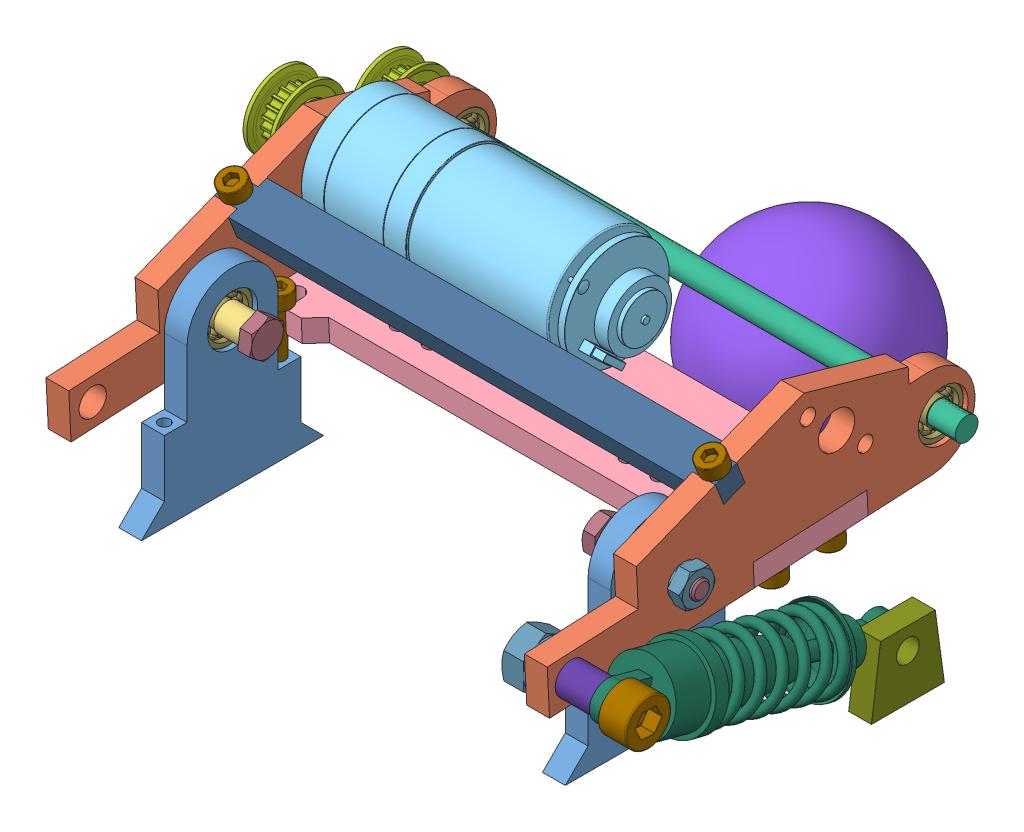
SolidWorks assembly tribla-better-assembly, configuration Default. Lengths in mm.
Overall size (140.2 70.72 132.36).
38 component instances, 17 part files, 67 mates.
Components (placement in the parent):
- tribla-jalg-4: tribla-jalg [Default] at (0.7792 -42.4947 66.2972) size (5 42 40)
- tribla-jalg-5: tribla-jalg [Default] at (93.7792 -42.4947 66.2972) size (5 42 40)
- tribla-side-3: tribla-side [Default] at (-0.2208 -6.2566 33.7735) x (0 -0.050794 0.998709) z (-1 0 0) size (94 31 5)
- tribla-little-ring-5: tribla-little-ring [Default] at (-5.2208 -10.4947 66.2972) x (0 -0.211085 -0.977468) z (0 -0.977468 0.211085) size (6 6 6)
- stabiliti-plane-2: stabiliti-plane [Default] at (104.7792 -19.82 40.9277) x (-1 0 0) z (0 0.050794 -0.998709) size (110 5 27)
- Pololu 25D gear motor with encoder part no 2275-2: Pololu 25D gear motor with encoder part no 2275 [Default] at (4.7792 1.2239 32.762) x (0 -0.679948 -0.73326) z (-1 0 0) size (25 25 75.81)
- tribla-little-ring-6: tribla-little-ring [Default] at (4.6292 -10.4947 66.2972) x (0 0.653622 -0.756821) z (0 -0.756821 -0.653622) size (6 6 6)
- tribla-side-4: tribla-side [Default] at (104.7792 -6.2566 33.7735) x (0 -0.050794 0.998709) z (-1 0 0) size (94 31 5)
- tribla-voll-2: tribla-voll [Default] at (47.3698 -10.4088 11.7103) x (-1 0 0) z (0 0.768447 -0.639913) size (120 5 5)
- tribla-rihmaratas'-3: tribla-rihmaratas' [Default] at (-10.8208 1.2239 32.762) x (0 0.354819 -0.934935) z (1 0 0) size (16.1 16.1 12.2)
- tribla-rihmaratas'-4: tribla-rihmaratas' [Default] at (-10.8208 -7.5994 9.3708) x (0 0.513074 -0.858344) z (1 0 0) size (16.1 16.1 12.2)
- tribla-little-ring-7: tribla-little-ring [Default] at (104.7792 -10.4947 66.2972) x (0 -0.429217 0.903201) z (0 -0.903201 -0.429217) size (6 6 6)
- tribla-little-ring-8: tribla-little-ring [Default] at (88.7792 -10.4947 66.2972) x (0 -0.057805 -0.998328) z (0 -0.998328 0.057805) size (6 6 6)
- ball-1: ball [Default] at (53.0779 -30.3345 -12.9168) size (43 43 43)
- socket head cap screw_iso-1: socket head cap screw_iso [ISO 4762 M3 x 10 --- 10C] at (96.2792 -21.8765 53.7972) x (0 -1 0) z (0.622703 0 0.782458) size (13 5.5 5.5)
- tribla-small-support-1: tribla-small-support [Default] at (104.7792 5.2258 53.9342) x (0 -0.368295 0.929709) z (-1 0 0) size (9 5 110)
- socket head cap screw_iso-4: socket head cap screw_iso [ISO 4762 M3 x 12 --- 12C] at (102.277 7.8744 58.1441) x (0 -0.929709 -0.368295) z (-0.694748 0.264898 -0.668696) size (15 5.5 5.5)
- socket head cap screw_iso-5: socket head cap screw_iso [ISO 4762 M3 x 12 --- 12C] at (-2.7185 7.8744 58.1441) x (0 -0.929709 -0.368295) z (-0.38626 0.339712 -0.857554) size (15 5.5 5.5)
- socket head cap screw_iso-6: socket head cap screw_iso [ISO 4762 M3 x 10 --- 10C] at (-2.7208 -22.3985 44.4143) x (0 0.998709 0.050794) z (-0.091557 -0.050581 0.994514) size (13 5.5 5.5)
- socket head cap screw_iso-7: socket head cap screw_iso [ISO 4762 M3 x 10 --- 10C] at (102.2792 -21.7636 31.9305) x (0 0.998709 0.050794) z (-0.091557 -0.050581 0.994514) size (13 5.5 5.5)
- socket head cap screw_iso-8: socket head cap screw_iso [ISO 4762 M3 x 10 --- 10C] at (-2.7208 -21.7636 31.9305) x (0 0.998709 0.050794) z (-0.091557 -0.050581 0.994514) size (13 5.5 5.5)
- socket head cap screw_iso-9: socket head cap screw_iso [ISO 4762 M3 x 10 --- 10C] at (102.2792 -22.3985 44.4143) x (0 0.998709 0.050794) z (-0.091557 -0.050581 0.994514) size (13 5.5 5.5)
- socket countersunk head screw_iso-3: socket countersunk head screw_iso [ISO 10642 - M3 x 12 --- 12C] at (-5.2208 -4.4735 26.4541) x (1 0 0) z (0 -0.048949 0.998801) size (12 5.54 5.54)
- socket countersunk head screw_iso-4: socket countersunk head screw_iso [ISO 10642 - M3 x 12 --- 12C] at (-5.2208 6.9212 39.07) x (1 0 0) z (0 0.256767 0.966473) size (12 5.54 5.54)
- socket head cap screw_iso-10: socket head cap screw_iso [ISO 4762 M3 x 20 --- 20N] at (3.2792 -11.5874 53.7972) x (0 -1 0) z (-0.920539 0 0.390651) size (23 5.5 5.5)
- angular contact ball bearing_68_iso-2: angular contact ball bearing_68_iso [ISO 15 ABB - 194 - Full,DE,AC,Full_68] at (-2.2208 -7.5994 9.3708) size (4 11 11)
- angular contact ball bearing_68_iso-3: angular contact ball bearing_68_iso [ISO 15 ABB - 194 - Full,DE,AC,Full_68] at (101.7792 -7.5994 9.3708) size (4 11 11)
- angular contact ball bearing_68_iso-4: angular contact ball bearing_68_iso [ISO 15 ABB - 194 - Full,DE,AC,Full_68] at (2.7792 -10.4947 66.2972) x (1 0 0) z (0 -0.345027 0.938593) size (4 11 11)
- angular contact ball bearing_68_iso-5: angular contact ball bearing_68_iso [ISO 15 ABB - 194 - Full,DE,AC,Full_68] at (96.7792 -10.4947 66.2972) size (4 11 11)
- hex bolt gradeb_iso-1: hex bolt gradeb_iso [ISO 4015 - M4 x 20 x 14-C] at (85.9792 -10.4947 66.2972) size (22.8 8.08 7)
- hex bolt gradeb_iso-2: hex bolt gradeb_iso [ISO 4015 - M4 x 20 x 14-C] at (13.4292 -10.4947 66.2972) x (-1 0 0) z (0 -0.924225 -0.381849) size (22.8 8.08 7)
- hex nut style 1 gradeab_iso-2: hex nut style 1 gradeab_iso [Hexagon Nut ISO - 4032 - M4 - W - N] at (-8.4208 -10.4947 66.2972) x (0 0.707107 0.707107) z (-1 0 0) size (7 8.08 3.2)
- hex nut style 1 gradeab_iso-3: hex nut style 1 gradeab_iso [Hexagon Nut ISO - 4032 - M4 - W - N] at (107.9792 -10.4947 66.2972) x (0 -0.615832 -0.787878) z (1 0 0) size (7 8.08 3.2)
- Amortecedor (PRONTO)-1: Amortecedor (PRONTO) [Valor predeterminado] at (114.2792 -20.43 77.5011) x (0 0.964991 -0.262284) z (1 0 0) size (17 68 17)
- tribla-amort-plaadidetail1-1: tribla-amort-plaadidetail1 [Default] at (115.7792 -32.4947 33.1114) size (5 14.77 16)
- tribla-amort-washer-1: tribla-amort-washer [Default] at (104.7792 -16.7581 91.011) x (0 -1 0) z (0 0 1) size (7 8 7)
- socket head cap screw_iso-11: socket head cap screw_iso [ISO 4762 M6 x 20 --- 20C] at (121.7792 -16.7581 91.011) x (-1 0 0) z (0 -0.555666 -0.831405) size (26 10 10)
- hex nut style 1 gradeab_iso-4: hex nut style 1 gradeab_iso [Hexagon Nut ISO - 4032 - M6 - W - C] at (94.5792 -16.7581 91.011) x (0 0 1) z (-1 0 0) size (10 11.55 5.2)
Mates (geometry in assembly coordinates):
- Coincident53: coincident anti-aligned: circle of tribla-side-3; circle of tribla-little-ring-5
- Coincident55: coincident aligned: line of tribla-side-3 through (-5.2208 -14.7263 51.0626) axis (0 0.050794 -0.998709); line of stabiliti-plane-2 through (-5.2208 -14.7263 51.0626) axis (0 0.050794 -0.998709)
- Coincident57: coincident aligned: line of tribla-side-3 through (-5.2208 -19.7198 50.8086) axis (0 0.998709 0.050794); line of stabiliti-plane-2 through (-5.2208 -19.7198 50.8086) axis (0 0.998709 0.050794)
- Concentric25: concentric anti-aligned: cylinder of tribla-side-3 through (-5.2208 1.2239 32.762) axis (-1 0 0) radius 4; cylinder of Pololu 25D gear motor with encoder part no 2275-2 through (-2.7208 1.2239 32.762) axis (1 0 0) radius 3.5
- Coincident59: coincident anti-aligned: plane of tribla-side-3 through (-0.2208 -6.2566 33.7735) normal (1 0 0); plane of Pololu 25D gear motor with encoder part no 2275-2 through (-0.2208 1.2239 32.762) normal (-1 0 0)
- Coincident64: coincident anti-aligned: line of stabiliti-plane-2 through (104.7792 -14.7263 51.0626) axis (0 0.050794 -0.998709); line of tribla-side-4 through (104.7792 -13.4564 26.0949) axis (0 -0.050794 0.998709)
- Coincident65: coincident anti-aligned: line of stabiliti-plane-2 through (104.7792 -19.7198 50.8086) axis (0 0.998709 0.050794); line of tribla-side-4 through (104.7792 -14.7263 51.0626) axis (0 -0.998709 -0.050794)
- Concentric29: concentric anti-aligned: cylinder of tribla-voll-2 through (109.9342 -7.5994 9.3708) axis (1 0 0) radius 2.3; cylinder of tribla-rihmaratas'-4 through (-4.9408 -7.5994 9.3708) axis (-1 0 0) radius 2
- Concentric30: concentric anti-aligned: cylinder of Pololu 25D gear motor with encoder part no 2275-2 through (-12.7208 1.2239 32.762) axis (1 0 0) radius 2; cylinder of tribla-rihmaratas'-3 through (-4.9408 1.2239 32.762) axis (-1 0 0) radius 2
- Coincident71: coincident aligned: circle of tribla-side-4; circle of tribla-little-ring-7
- Parallel2: parallel aligned: plane of tribla-jalg-4 through (5.7792 -42.4947 86.2972) normal (0 -1 0); plane of tribla-jalg-5 through (98.7792 -42.4947 86.2972) normal (0 -1 0)
- Coincident74: coincident aligned: line of tribla-side-3 through (-5.2208 1.3575 52.8734) axis (0 -0.368295 0.929709); line of tribla-small-support-1 through (-5.2208 1.3575 52.8734) axis (0 -0.368295 0.929709)
- Coincident75: coincident anti-aligned: line of tribla-side-4 through (104.7792 4.1646 59.3635) axis (0 -0.929709 -0.368295); line of tribla-small-support-1 through (104.7792 -0.484 57.522) axis (0 0.929709 0.368295)
- Concentric35: concentric aligned: cylinder of tribla-small-support-1 through (102.277 5.0853 57.0392) axis (0 0.929709 0.368295) radius 1.25; cylinder of socket head cap screw_iso-4 through (102.277 37.3927 69.8375) axis (0 0.929709 0.368295) radius 1.5
- Concentric36: concentric aligned: cylinder of tribla-small-support-1 through (-2.7185 5.0853 57.0392) axis (0 0.929709 0.368295) radius 1.25; cylinder of socket head cap screw_iso-5 through (-2.7185 37.3927 69.8375) axis (0 0.929709 0.368295) radius 1.5
- Coincident76: coincident anti-aligned: plane of tribla-small-support-1 through (-5.2208 6.006 54.7149) normal (0 0.929709 0.368295); plane of socket head cap screw_iso-5 through (-5.2551 4.6941 58.0267) normal (0 -0.929709 -0.368295)
- Coincident77: coincident anti-aligned: plane of tribla-small-support-1 through (-5.2208 6.006 54.7149) normal (0 0.929709 0.368295); plane of socket head cap screw_iso-4 through (100.299 4.3816 58.8155) normal (0 -0.929709 -0.368295)
- Concentric37: concentric aligned: cylinder of stabiliti-plane-2 through (-2.7208 -19.4024 44.5667) axis (0 -0.998709 -0.050794) radius 1.5; cylinder of socket head cap screw_iso-6 through (-2.7208 -54.1075 42.8016) axis (0 -0.998709 -0.050794) radius 1.5
- Coincident78: coincident anti-aligned: plane of stabiliti-plane-2 through (-5.2208 -18.3484 23.8435) normal (0 -0.998709 -0.050794); plane of socket head cap screw_iso-6 through (-5.4592 -19.3896 44.3152) normal (0 0.998709 0.050794)
- Concentric38: concentric aligned: cylinder of stabiliti-plane-2 through (-2.7208 -18.7674 32.0828) axis (0 -0.998709 -0.050794) radius 1.5; cylinder of socket head cap screw_iso-8 through (-2.7208 -53.4726 30.3177) axis (0 -0.998709 -0.050794) radius 1.5
- Coincident79: coincident anti-aligned: plane of stabiliti-plane-2 through (-5.2208 -18.3484 23.8435) normal (0 -0.998709 -0.050794); plane of socket head cap screw_iso-8 through (-5.4592 -18.7547 31.8314) normal (0 0.998709 0.050794)
- Concentric39: concentric aligned: cylinder of stabiliti-plane-2 through (102.2792 -18.7674 32.0828) axis (0 -0.998709 -0.050794) radius 1.5; cylinder of socket head cap screw_iso-7 through (102.2792 -53.4726 30.3177) axis (0 -0.998709 -0.050794) radius 1.5
- Coincident80: coincident anti-aligned: plane of stabiliti-plane-2 through (-5.2208 -18.3484 23.8435) normal (0 -0.998709 -0.050794); plane of socket head cap screw_iso-7 through (99.5408 -18.7547 31.8314) normal (0 0.998709 0.050794)
- Concentric40: concentric aligned: cylinder of stabiliti-plane-2 through (102.2792 -19.4024 44.5667) axis (0 -0.998709 -0.050794) radius 1.5; cylinder of socket head cap screw_iso-9 through (102.2792 -54.1075 42.8016) axis (0 -0.998709 -0.050794) radius 1.5
- Coincident81: coincident anti-aligned: plane of stabiliti-plane-2 through (-5.2208 -18.3484 23.8435) normal (0 -0.998709 -0.050794); plane of socket head cap screw_iso-9 through (99.5408 -19.3896 44.3152) normal (0 0.998709 0.050794)
- Concentric41: concentric aligned: cylinder of tribla-side-3 through (-5.2208 -4.4735 26.4541) axis (-1 0 0) radius 1.7; cylinder of socket countersunk head screw_iso-3 through (-5.2208 -4.4735 26.4541) axis (-1 0 0) radius 1.5
- Concentric43: concentric aligned: cylinder of tribla-side-3 through (-5.2208 6.9212 39.07) axis (-1 0 0) radius 1.7; cylinder of socket countersunk head screw_iso-4 through (-5.2208 6.9212 39.07) axis (-1 0 0) radius 1.5
- Concentric44: concentric aligned: cylinder of tribla-jalg-4 through (3.2792 -24.9947 53.7972) axis (0 1 0) radius 1.25; cylinder of socket head cap screw_iso-10 through (3.2792 20.1626 53.7972) axis (0 1 0) radius 1.5
- Concentric45: concentric anti-aligned: cylinder of tribla-side-4 through (99.7792 -7.5994 9.3708) axis (-1 0 0) radius 5.5; cylinder of angular contact ball bearing_68_iso-3 through (81.1417 -7.5994 9.3708) axis (1 0 0) radius 5.5
- Concentric46: concentric anti-aligned: circle of tribla-side-4; circle of angular contact ball bearing_68_iso-3
- Coincident82: coincident aligned: plane of tribla-side-4 through (99.7792 -6.2566 33.7735) normal (-1 0 0); plane of angular contact ball bearing_68_iso-3 through (99.7792 -4.5494 9.3708) normal (-1 0 0)
- Concentric47: concentric anti-aligned: cylinder of tribla-side-3 through (-5.2208 -7.5994 9.3708) axis (-1 0 0) radius 5.5; cylinder of angular contact ball bearing_68_iso-2 through (-22.8583 -7.5994 9.3708) axis (1 0 0) radius 5.5
- Coincident83: coincident aligned: plane of angular contact ball bearing_68_iso-2 through (-0.2208 -2.2494 9.3708) normal (1 0 0); plane of tribla-side-3 through (-0.2208 -6.2566 33.7735) normal (1 0 0)
- Concentric48: concentric anti-aligned: cylinder of tribla-jalg-4 through (0.7792 -10.4947 66.2972) axis (-1 0 0) radius 5.5; cylinder of angular contact ball bearing_68_iso-4 through (-17.8583 -10.4947 66.2972) axis (1 0 0) radius 5.5
- Coincident84: coincident aligned: plane of tribla-jalg-4 through (0.7792 -10.4947 66.2972) normal (-1 0 0); plane of angular contact ball bearing_68_iso-4 through (0.7792 -6.0129 67.9447) normal (-1 0 0)
- Concentric49: concentric anti-aligned: cylinder of tribla-jalg-5 through (93.7792 -10.4947 66.2972) axis (-1 0 0) radius 5.5; cylinder of angular contact ball bearing_68_iso-5 through (76.1417 -10.4947 66.2972) axis (1 0 0) radius 5.5
- Coincident85: coincident aligned: plane of tribla-jalg-5 through (98.7792 -10.4947 66.2972) normal (1 0 0); plane of angular contact ball bearing_68_iso-5 through (98.7792 -8.3447 66.2972) normal (1 0 0)
- Coincident87: coincident aligned: circle of tribla-little-ring-6; circle of angular contact ball bearing_68_iso-4
- Concentric51: concentric anti-aligned: cylinder of tribla-little-ring-6 through (10.6292 -10.4947 66.2972) axis (-1 0 0) radius 2; cylinder of hex bolt gradeb_iso-2 through (13.4292 -10.4947 66.2972) axis (1 0 0) radius 2
- Coincident88: coincident anti-aligned: plane of tribla-little-ring-6 through (10.6292 -10.4947 66.2972) normal (1 0 0); plane of hex bolt gradeb_iso-2 through (10.6292 -8.9514 62.562) normal (-1 0 0)
- Concentric52: concentric aligned: circle of tribla-little-ring-8; circle of angular contact ball bearing_68_iso-5
- Coincident90: coincident anti-aligned: plane of tribla-little-ring-8 through (94.7792 -10.4947 66.2972) normal (1 0 0); plane of angular contact ball bearing_68_iso-5 through (94.7792 -7.4447 66.2972) normal (-1 0 0)
- Concentric53: concentric aligned: cylinder of tribla-little-ring-8 through (94.7792 -10.4947 66.2972) axis (-1 0 0) radius 2; cylinder of hex bolt gradeb_iso-1 through (85.9792 -10.4947 66.2972) axis (-1 0 0) radius 2
- Coincident91: coincident anti-aligned: plane of tribla-little-ring-8 through (88.7792 -10.4947 66.2972) normal (-1 0 0); plane of hex bolt gradeb_iso-1 through (88.7792 -6.4532 66.2972) normal (1 0 0)
- Coincident92: coincident anti-aligned: plane of tribla-side-3 through (-5.2208 -6.2566 33.7735) normal (-1 0 0); plane of hex nut style 1 gradeab_iso-2 through (-5.2208 -15.4444 61.3475) normal (1 0 0)
- Concentric54: concentric anti-aligned: cylinder of hex bolt gradeb_iso-2 through (13.4292 -10.4947 66.2972) axis (1 0 0) radius 2; cylinder of hex nut style 1 gradeab_iso-2 through (-5.2208 -10.4947 66.2972) axis (-1 0 0) radius 1.65
- Coincident93: coincident anti-aligned: plane of tribla-side-4 through (104.7792 -6.2566 33.7735) normal (1 0 0); plane of hex nut style 1 gradeab_iso-3 through (104.7792 -6.1838 71.8124) normal (-1 0 0)
- Concentric55: concentric anti-aligned: cylinder of hex bolt gradeb_iso-1 through (85.9792 -10.4947 66.2972) axis (-1 0 0) radius 2; cylinder of hex nut style 1 gradeab_iso-3 through (104.7792 -10.4947 66.2972) axis (1 0 0) radius 1.65
- Coincident94: coincident anti-aligned: circle of Amortecedor (PRONTO)-1; circle of tribla-amort-plaadidetail1-1
- Coincident95: coincident aligned: plane of tribla-amort-plaadidetail1-1 through (120.7792 -42.4947 25.1114) normal (0 -1 0); plane of tribla-jalg-4 through (5.7792 -42.4947 86.2972) normal (0 -1 0)
- Parallel4: parallel aligned: plane of tribla-jalg-5 through (98.7792 -10.4947 66.2972) normal (1 0 0); plane of tribla-amort-plaadidetail1-1 through (120.7792 -32.4947 33.1114) normal (1 0 0)
- Coincident96: coincident aligned: plane of tribla-jalg-4 through (5.7792 -42.4947 86.2972) normal (0 -1 0); plane of tribla-jalg-5 through (98.7792 -42.4947 86.2972) normal (0 -1 0)
- Concentric56: concentric anti-aligned: cylinder of tribla-little-ring-7 through (98.7792 -10.4947 66.2972) axis (1 0 0) radius 2; cylinder of hex bolt gradeb_iso-1 through (85.9792 -10.4947 66.2972) axis (-1 0 0) radius 2
- Coincident98: coincident anti-aligned: plane of tribla-little-ring-7 through (98.7792 -10.4947 66.2972) normal (-1 0 0); plane of angular contact ball bearing_68_iso-5 through (98.7792 -8.3447 66.2972) normal (1 0 0)
- Coincident100: coincident aligned: plane of tribla-side-3 through (-5.2208 -6.2566 33.7735) normal (-1 0 0); plane of socket countersunk head screw_iso-4 through (-5.2208 6.9212 39.07) normal (-1 0 0)
- Coincident101: coincident aligned: plane of tribla-side-3 through (-5.2208 -6.2566 33.7735) normal (-1 0 0); plane of socket countersunk head screw_iso-3 through (-5.2208 -4.4735 26.4541) normal (-1 0 0)
- Coincident102: coincident anti-aligned: plane of tribla-side-3 through (-5.2208 -6.2566 33.7735) normal (-1 0 0); plane of tribla-rihmaratas'-3 through (-5.2208 1.2239 32.762) normal (1 0 0)
- Concentric57: concentric anti-aligned: cylinder of tribla-little-ring-5 through (0.7792 -10.4947 66.2972) axis (-1 0 0) radius 2; cylinder of hex bolt gradeb_iso-2 through (13.4292 -10.4947 66.2972) axis (1 0 0) radius 2
- Coincident103: coincident anti-aligned: plane of tribla-little-ring-5 through (0.7792 -10.4947 66.2972) normal (1 0 0); plane of angular contact ball bearing_68_iso-4 through (0.7792 -7.632 67.3495) normal (-1 0 0)
- Concentric58: concentric aligned: cylinder of tribla-voll-2 through (109.9342 -7.5994 9.3708) axis (1 0 0) radius 2.5; cylinder of angular contact ball bearing_68_iso-2 through (-22.8583 -7.5994 9.3708) axis (1 0 0) radius 2
- Coincident104: coincident anti-aligned: plane of tribla-side-3 through (-5.2208 -6.2566 33.7735) normal (-1 0 0); plane of tribla-rihmaratas'-4 through (-5.2208 -7.5994 9.3708) normal (1 0 0)
- Coincident106: coincident aligned: circle of tribla-side-4; circle of tribla-amort-washer-1
- Coincident108: coincident anti-aligned: circle of Amortecedor (PRONTO)-1; circle of tribla-amort-washer-1
- Concentric59: concentric aligned: cylinder of Amortecedor (PRONTO)-1 through (104.294 -16.7581 91.011) axis (1 0 0) radius 3; cylinder of socket head cap screw_iso-11 through (153.5292 -16.7581 91.011) axis (1 0 0) radius 3
- Concentric60: concentric anti-aligned: cylinder of socket head cap screw_iso-11 through (153.5292 -16.7581 91.011) axis (1 0 0) radius 3; cylinder of hex nut style 1 gradeab_iso-4 through (99.7792 -16.7581 91.011) axis (-1 0 0) radius 2.5
- Coincident109: coincident anti-aligned: plane of tribla-side-4 through (99.7792 -6.2566 33.7735) normal (-1 0 0); plane of hex nut style 1 gradeab_iso-4 through (99.7792 -16.7581 81.011) normal (1 0 0)
- Coincident110: coincident anti-aligned: plane of Amortecedor (PRONTO)-1 through (115.7792 -19.5689 95.9201) normal (1 0 0); plane of socket head cap screw_iso-11 through (115.7792 -12.601 88.2326) normal (-1 0 0)
